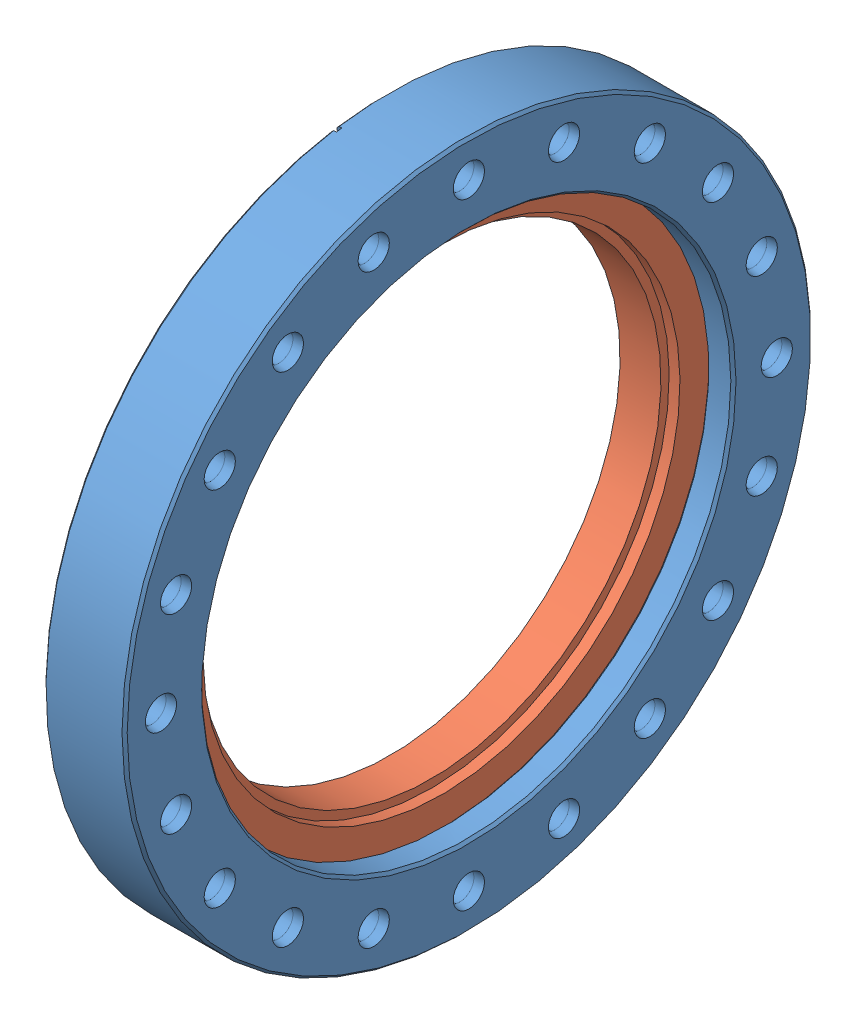
SolidWorks assembly 100030, configuration Default. Lengths in mm.
Overall size (23.88 240.42 240.42).
2 component instances, 2 part files, 2 mates.
Components (placement in the parent):
- 915008-1: 915008 [Default] at (60.5906 96.5417 163.1759) size (23.88 202.44 202.44)
- 953948-1: 953948 [Default] at (76.4402 96.5417 163.1759) x (-1 0 0) z (0 0.785501 0.61886) size (15.19 171.2 171.2)
Mates (geometry in assembly coordinates):
- Concentric1: concentric anti-aligned: cylinder of 915008-1 through (60.5906 96.5417 163.1759) axis (-1 0 0) radius 101.219; cylinder of 953948-1 through (76.4402 96.5417 163.1759) axis (1 0 0) radius 85.598
- Coincident1: coincident anti-aligned: plane of 915008-1 through (76.4402 182.2667 163.1759) normal (-1 0 0); plane of 953948-1 through (76.4402 43.5685 230.4132) normal (1 0 0)
